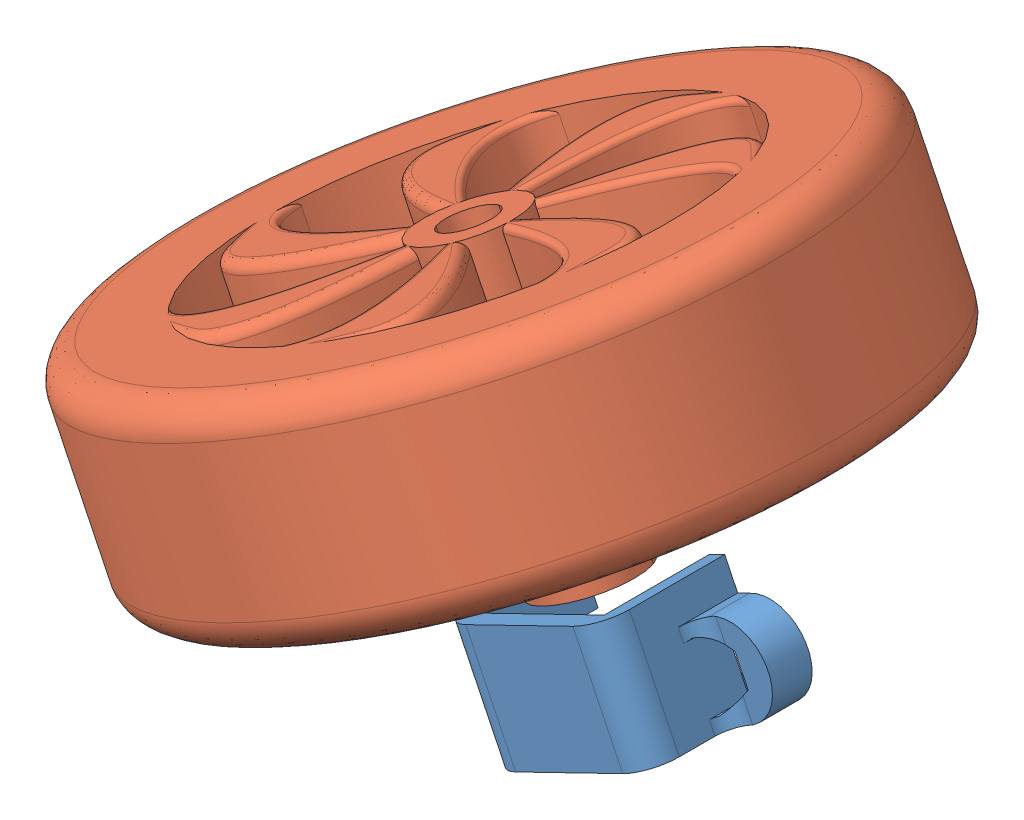
SolidWorks assembly wheel without motor assembly, configuration Default. Lengths in mm.
Overall size (71.05 57.03 65).
2 component instances, 2 part files, 0 mates.
Components (placement in the parent):
- Part2_1-1: Part2_1 [Default] at (-27.1771 54.5716 19.0847) x (-0.899278 -0.437378 0) z (-0.437378 0.899278 0) size (29.6 12.6 11.51)
- wheel1-1: wheel1 [Default] at (-42.4704 85.0101 24.0355) x (-0.899278 -0.437378 0) z (0 0 1) size (65 28.8 65)
